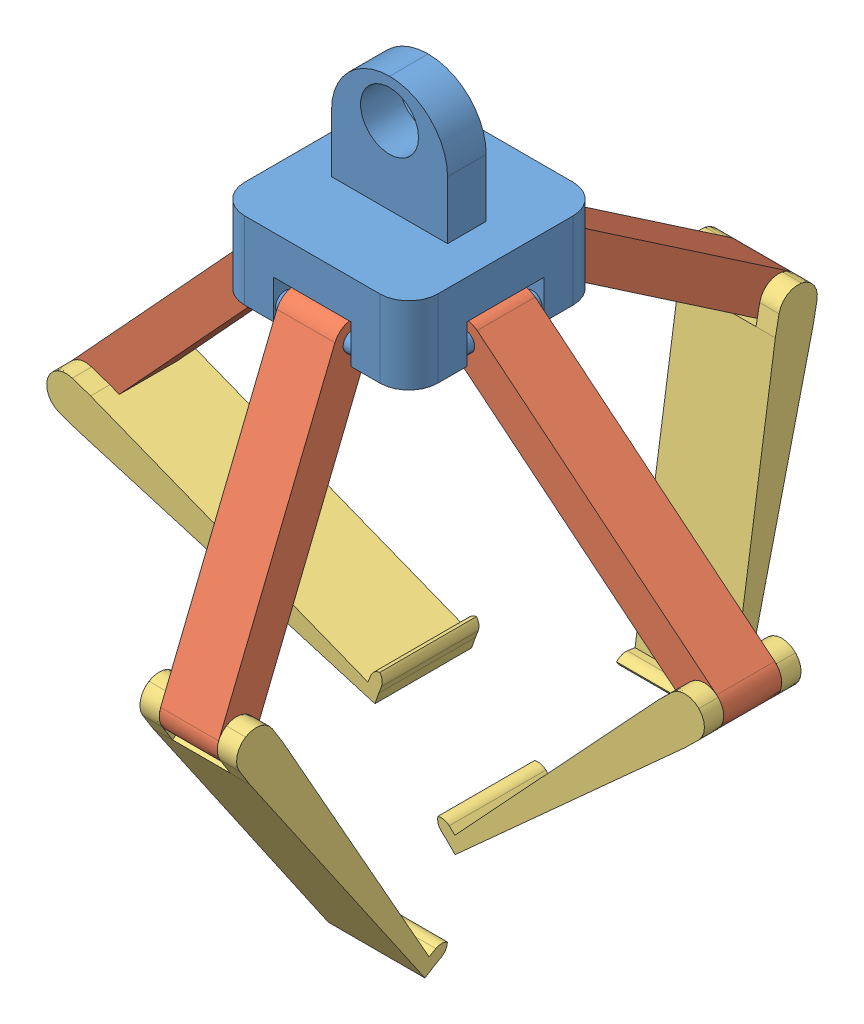
SolidWorks assembly Claw Assmbley, configuration Default. Lengths in mm.
Overall size (174.25 227.4 154.03).
9 component instances, 3 part files, 16 mates.
Components (placement in the parent):
- Claw holder-1: Claw holder [Default] at (21.4988 46.7355 81.0528) size (50 100 50)
- Finger 1-1: Finger 1 [Default] at (-27.5868 0.3014 73.5528) x (0.735853 -0.677142 0) z (0 0 1) size (10 90 15)
- Finger 2-1: Finger 2 [Default] at (8.9988 -48.6429 130.4696) x (0 0.529318 -0.848423) z (1 0 0) size (11.16 90.09 25)
- Finger 2-2: Finger 2 [Default] at (-49.9444 -30.7589 68.5528) x (0.325247 0.945629 0) z (0 0 1) size (11.16 90.09 25)
- Finger 2-3: Finger 2 [Default] at (101.8784 -24.4044 93.5528) x (-0.702007 0.71217 0) z (0 0 -1) size (11.16 90.09 25)
- Finger 2-4: Finger 2 [Default] at (33.9988 -20.1912 -6.132) x (0 0.189449 0.981891) z (-1 0 0) size (11.16 90.09 25)
- Finger 1-2: Finger 1 [Default] at (13.9988 -7.3326 118.0844) x (0 -0.375792 -0.926704) z (1 0 0) size (10 90 15)
- Finger 1-3: Finger 1 [Default] at (74.469 4.4206 73.5528) x (0.632874 0.774255 0) z (0 0 1) size (10 90 15)
- Finger 1-4: Finger 1 [Default] at (28.9988 7.2269 25.9867) x (0 -0.826651 0.562716) z (-1 0 0) size (10 90 15)
Mates (geometry in assembly coordinates):
- Concentric1: concentric aligned: cylinder of Claw holder-1 through (43.4988 29.7355 63.9817) axis (0 0 1) radius 2.5; cylinder of Finger 1-3 through (43.4988 29.7355 66.4817) axis (0 0 1) radius 2.5
- Distance1: distance = 2.5 mm anti-aligned: plane of Claw holder-1 through (46.4988 36.7355 91.0528) normal (0 0 -1); plane of Finger 1-3 through (74.469 4.4206 88.5528) normal (0 0 1)
- Concentric2: concentric aligned: cylinder of Finger 2-3 through (105.4392 -20.8944 66.4817) axis (0 0 1) radius 2.5; cylinder of Finger 1-3 through (105.4392 -20.8944 66.4817) axis (0 0 1) radius 2.5
- Distance3: distance = 0 mm anti-aligned: plane of Finger 1-3 through (74.469 4.4206 88.5528) normal (0 0 1); plane of Finger 2-3 through (105.3884 -27.9653 88.5528) normal (0 0 -1)
- Concentric3: concentric anti-aligned: cylinder of Claw holder-1 through (4.4278 29.7355 59.0528) axis (1 0 0) radius 2.5; cylinder of Finger 1-4 through (36.0699 29.7355 59.0528) axis (-1 0 0) radius 2.5
- Distance4: distance = 2.5 mm anti-aligned: plane of Claw holder-1 through (11.4988 36.7355 56.0528) normal (1 0 0); plane of Finger 1-4 through (13.9988 7.2269 25.9867) normal (-1 0 0)
- Concentric4: concentric anti-aligned: cylinder of Finger 2-4 through (6.9278 -15.2817 -7.0793) axis (1 0 0) radius 2.5; cylinder of Finger 1-4 through (36.0699 -15.2817 -7.0793) axis (-1 0 0) radius 2.5
- Coincident5: coincident anti-aligned: plane of Finger 2-4 through (28.9988 -21.1384 -11.0415) normal (-1 0 0); plane of Finger 1-4 through (28.9988 7.2269 25.9867) normal (1 0 0)
- Concentric5: concentric aligned: cylinder of Claw holder-1 through (-0.5012 29.7355 63.9817) axis (0 0 1) radius 2.5; cylinder of Finger 1-1 through (-0.5012 29.7355 66.4817) axis (0 0 1) radius 2.5
- Distance5: distance = 2.5 mm anti-aligned: plane of Finger 1-1 through (-27.5868 0.3014 73.5528) normal (0 0 -1); plane of Claw holder-1 through (-3.5012 36.7355 71.0528) normal (0 0 1)
- Concentric6: concentric anti-aligned: cylinder of Finger 1-1 through (-54.6725 -29.1327 66.4817) axis (0 0 1) radius 2.5; cylinder of Finger 2-2 through (-54.6725 -29.1327 95.6238) axis (0 0 -1) radius 2.5
- Coincident7: coincident anti-aligned: plane of Finger 1-1 through (-27.5868 0.3014 88.5528) normal (0 0 1); plane of Finger 2-2 through (-51.5706 -35.487 88.5528) normal (0 0 -1)
- Concentric7: concentric anti-aligned: cylinder of Claw holder-1 through (38.5699 29.7355 103.0528) axis (-1 0 0) radius 2.5; cylinder of Finger 1-2 through (6.9278 29.7355 103.0528) axis (1 0 0) radius 2.5
- Distance6: distance = 2.5 mm anti-aligned: plane of Claw holder-1 through (11.4988 36.7355 106.0528) normal (1 0 0); plane of Finger 1-2 through (13.9988 -7.3326 118.0844) normal (-1 0 0)
- Concentric8: concentric anti-aligned: cylinder of Finger 2-1 through (36.0699 -44.4008 133.1161) axis (-1 0 0) radius 2.5; cylinder of Finger 1-2 through (6.9278 -44.4008 133.1161) axis (1 0 0) radius 2.5
- Coincident9: coincident anti-aligned: plane of Finger 2-1 through (13.9988 -51.2895 134.7117) normal (1 0 0); plane of Finger 1-2 through (13.9988 -7.3326 118.0844) normal (-1 0 0)
